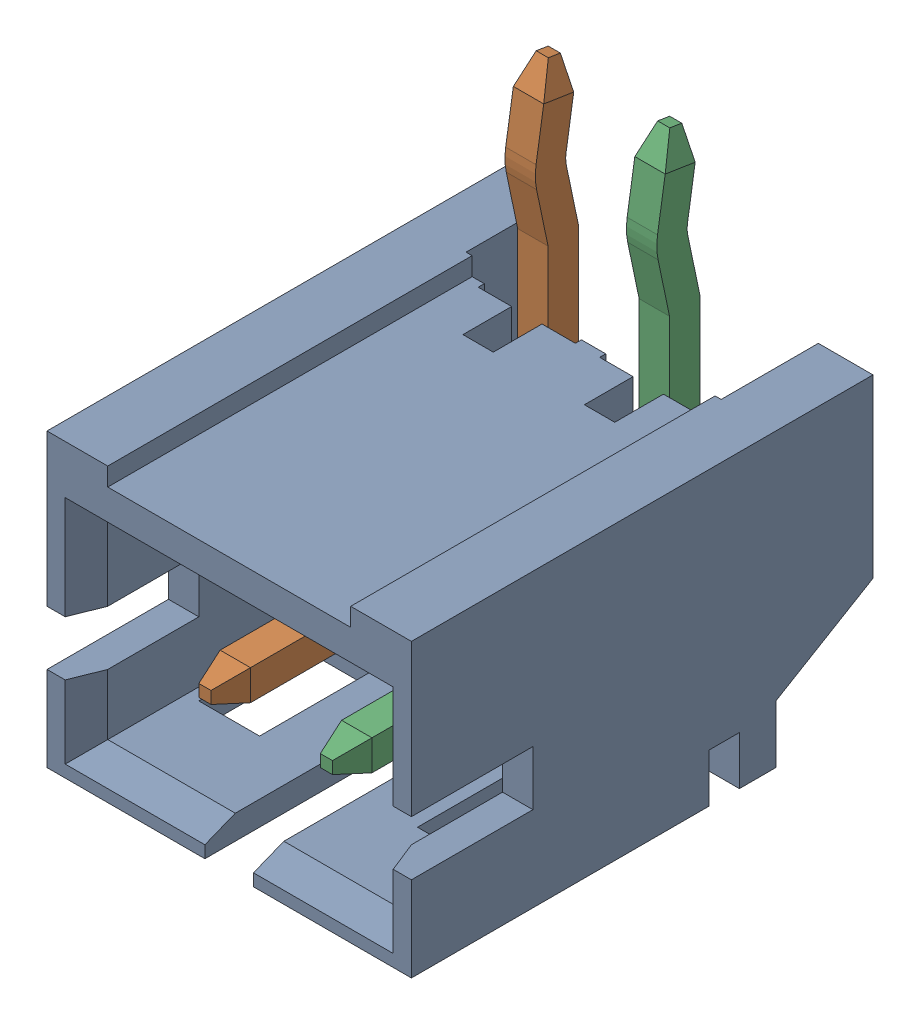
SolidWorks assembly 62000211722, configuration Default. Lengths in mm.
Overall size (6 8.09 7.6).
3 component instances, 2 part files, 0 mates.
Components (placement in the parent):
- 62000211722-1: 62000211722 [Default] at origin size (6 4.8 7.6)
- 6200xx11722_PIN1-1: 6200xx11722_PIN1 [Default] at (-1 1.645 -0.05) size (0.5 6.59 5.9)
- 6200xx11722_PIN1-2: 6200xx11722_PIN1 [Default] at (1 1.645 -0.05) size (0.5 6.59 5.9)
